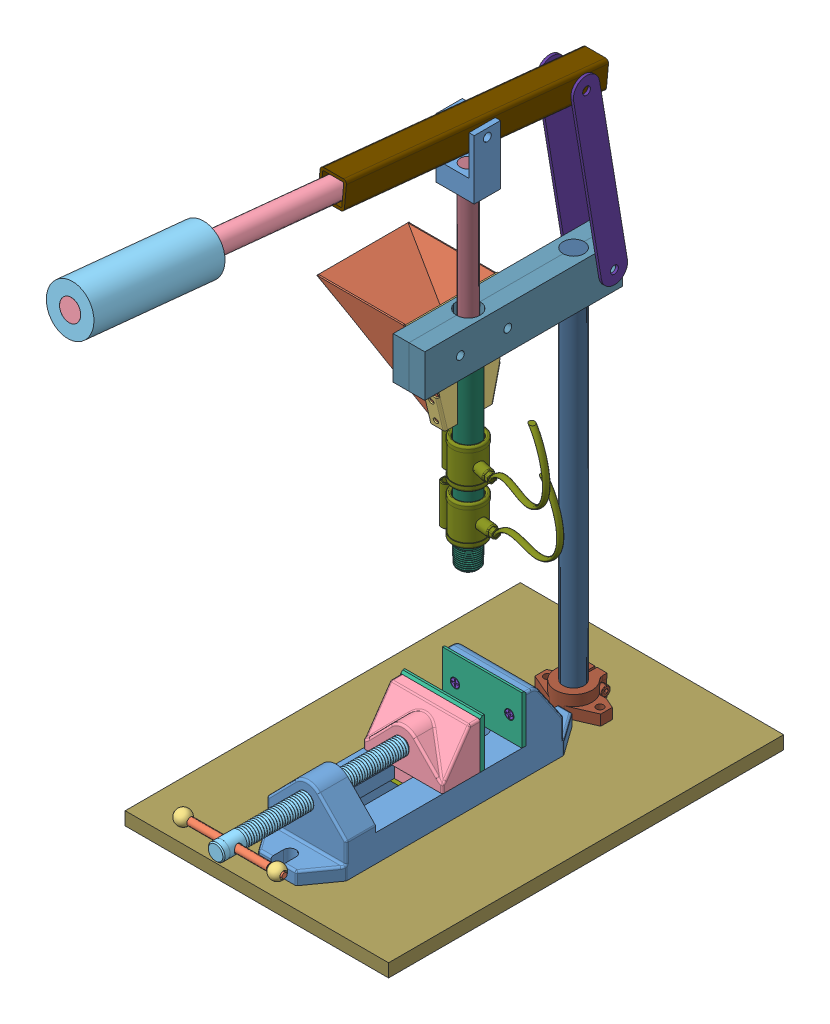
SolidWorks assembly Manual Injection, configuration Varsayılan. Lengths in mm.
Overall size (200 481.82 443.96).
32 component instances, 23 part files, 41 mates.
Components (placement in the parent):
- User Library-Vise-1-1: User Library-Vise-1 [Default] at (-149.6463 -94.0515 315.6053) x (0 0 -1) z (1 0 0) size (256.38 57.15 82.55)
  - User Library-Vise-1_Base-1: User Library-Vise-1_Base [Default] at origin size (209.55 55.56 60.32)
  - User Library-Vise-1_Handle-Rod (6)-1: User Library-Vise-1_Handle-Rod (6) [Default] at (-140.4938 38.1 0) size (5.56 5.56 82.55)
  - User Library-Vise-1_Handle-Ball (7)-1: User Library-Vise-1_Handle-Ball (7) [Default] at (-140.4938 38.1 35.7188) x (1 0 0) z (0 -1 0) size (11.11 10 11.11)
  - User Library-Vise-1_Handle-Ball (7)-2: User Library-Vise-1_Handle-Ball (7) [Default] at (-140.4938 38.1 -35.7188) x (1 0 0) z (0 1 0) size (11.11 10 11.11)
  - User Library-Vise-1_Sliding-Jaw-1: User Library-Vise-1_Sliding-Jaw [Default] at (4.7625 11.0871 0.0381) size (28.57 44.48 60.32)
  - User Library-Vise-1_Screw-1: User Library-Vise-1_Screw [Default] at (-134.1438 38.1 0) size (161.92 12.7 12.7)
  - User Library-Vise-1_Jaw-Plate-1: User Library-Vise-1_Jaw-Plate [Default] at (52.3875 38.8937 0) x (0 0 1) z (-1 0 0) size (60.32 36.51 3.17)
  - User Library-Vise-1_Jaw-Plate-2: User Library-Vise-1_Jaw-Plate [Default] at (20.6375 38.8937 0.0381) x (0 0 -1) z (1 0 0) size (60.32 36.51 3.17)
  - User Library-Vise-1_Retainer-Plate-1: User Library-Vise-1_Retainer-Plate [Default] at (4.7625 9.5504 0.0381) size (25.4 3.17 22.23)
  - flat head screw_ai-5: flat head screw_ai [CR-FHMS 0.138-32x0.375x0.375-N] at (50.7846 38.1 20.6375) size (9.53 6.2 6.2)
  - flat head screw_ai-6: flat head screw_ai [CR-FHMS 0.138-32x0.375x0.375-N] at (50.7846 38.1 -20.6375) size (9.53 6.2 6.2)
  - flat head screw_ai-7: flat head screw_ai [CR-FHMS 0.138-32x0.375x0.375-N] at (22.2404 38.1 20.6756) x (-1 0 0) z (0 1 0) size (9.53 6.2 6.2)
  - flat head screw_ai-8: flat head screw_ai [CR-FHMS 0.138-32x0.375x0.375-N] at (22.2404 38.1 -20.5994) x (-1 0 0) z (0 1 0) size (9.53 6.2 6.2)
  - User Library-Vise-1_Retaining-Screw-2: User Library-Vise-1_Retaining-Screw [HBOLT 0.2500-20x1x1-C] at (4.7625 3.1877 0.0381) x (0 1 0) z (0 0 1) size (30.18 12.85 11.13)
- 5-8inch  rod-2: 5-8inch  rod [Varsayılan] at (-149.6463 -94.0515 195.3553) size (16 300 16)
- support_shf16-1: support_shf16 [Default] at (-149.6463 -94.0515 195.3553) x (1 0 0) z (0 1 0) size (50 31 16)
- base-2: base [Varsayılan] at (-149.6463 -104.0515 285.8553) size (200 10 300)
- 12mm rod-1: 12mm rod [Varsayılan] at (-149.6463 116.8052 275.3553) x (0.940707 0 -0.33922) z (0 1 0) size (12 12 185)
- rod holder-1: rod holder [Varsayılan] at (-161.6463 189.9485 245.3553) x (0 0 -1) z (1 0 0) size (150 32 12)
- 4830K158_STD-WALL TYPE 304-304L SS THRD PIPE NIPPLE-1: 4830K158_STD-WALL TYPE 304-304L SS THRD PIPE NIPPLE [4830K158] at (-149.6463 113.3889 275.3553) x (0 1 0) z (0 0 1) size (152.69 17.99 18.02)
- 75x40 Nozzle Band Heater-1: 75x40 Nozzle Band Heater [Radial] at (-149.6463 55.7599 275.3553) x (-0.103457 0 0.994634) z (-0.994634 0 -0.103457) size (24 75.91 99.43)
- 75x40 Nozzle Band Heater-2: 75x40 Nozzle Band Heater [Radial] at (-149.6463 93.3169 275.3553) x (-0.219712 0 0.975565) z (-0.975565 0 -0.219712) size (24 75.91 99.43)
- rod holder-2: rod holder [Varsayılan] at (-137.6463 189.9485 245.3553) x (0 0 -1) z (-1 0 0) size (150 32 12)
- press handler-1: press handler [Varsayılan] at (-161.6463 254.0801 188.9449) x (0 0.98664 0.162918) z (-1 0 0) size (150 20 2)
- press handler-2: press handler [Varsayılan] at (-135.6463 254.0801 188.9449) x (0 0.98664 0.162918) z (-1 0 0) size (150 20 2)
- 1471T731_SOLID FRAMING-1: 1471T731_SOLID FRAMING [1471T731] at (-149.6463 326.1839 279.1364) x (1 0 0) z (0 0.099653 0.995022) size (20 20 200)
- handler bracket-1: handler bracket [Varsayılan] at (-149.6463 309.3052 265.3553) x (0 -1 0) z (0 0 1) size (45 29 20)
- feeder hole-1: feeder hole [Varsayılan] at (-160.5691 135.7576 275.3553) x (0 0 1) z (-0.707107 -0.707107 0) size (69.96 112.47 47.42)
- feeder hole back-1: feeder hole back [Varsayılan] at (-162.6463 189.9485 275.3553) x (0 0 1) z (-1 0 0) size (70 71.4 14)
- handle pipe-1: handle pipe [Varsayılan] at (-149.6463 331.1665 328.8875) x (-0.854746 -0.516462 0.051724) z (0 0.099653 0.995022) size (16 16 250)
- handle plastics-1: handle plastics [Varsayılan] at (-149.6463 346.1144 478.1408) x (0.970687 0.239151 -0.023951) z (0 0.099653 0.995022) size (36 36 100)
Mates (geometry in assembly coordinates):
- Eş Merkezli3: concentric anti-aligned: cylinder of 5-8inch  rod-2 through (-149.6463 205.9485 195.3553) axis (0 -1 0) radius 8; cylinder of support_shf16-1 through (-149.6463 -95.0515 195.3553) axis (0 1 0) radius 8
- Çakışık10: coincident aligned: plane of 5-8inch  rod-2 through (-149.6463 -94.0515 195.3553) normal (0 -1 0); plane of support_shf16-1 through (-135.6463 -94.0515 181.6381) normal (0 -1 0)
- Eş Merkezli5: concentric anti-aligned: cylinder of User Library-Vise-1-1/User Library-Vise-1_Base-1 through (-149.6463 -84.5265 410.8553) axis (0 -1 0) radius 4.7625; cylinder of base-2 through (-149.6463 -104.0515 410.8553) axis (0 1 0) radius 3
- Eş Merkezli6: concentric anti-aligned: cylinder of User Library-Vise-1-1/User Library-Vise-1_Base-1 through (-149.6463 -84.5265 220.3553) axis (0 -1 0) radius 4.7625; cylinder of base-2 through (-149.6463 -104.0515 220.3553) axis (0 1 0) radius 3
- Çakışık12: coincident anti-aligned: plane of User Library-Vise-1-1/User Library-Vise-1_Base-1 through (-119.4838 -94.0515 398.1553) normal (0 -1 0); plane of base-2 through (-149.6463 -94.0515 285.8553) normal (0 1 0)
- Çakışık13: coincident anti-aligned: plane of support_shf16-1 through (-135.6463 -94.0515 181.6381) normal (0 -1 0); plane of base-2 through (-149.6463 -94.0515 285.8553) normal (0 1 0)
- Eş Merkezli11: concentric anti-aligned: cylinder of 5-8inch  rod-2 through (-149.6463 205.9485 195.3553) axis (0 -1 0) radius 8; cylinder of rod holder-1 through (-149.6463 145.9485 195.3553) axis (0 1 0) radius 8
- Çakışık15: coincident aligned: plane of 5-8inch  rod-2 through (-149.6463 205.9485 195.3553) normal (0 1 0); plane of rod holder-1 through (-149.6463 205.9485 320.3553) normal (0 1 0)
- Eş Merkezli13: concentric anti-aligned: cylinder of 12mm rod-1 through (-149.6463 301.8052 275.3553) axis (0 -1 0) radius 6; cylinder of 4830K158_STD-WALL TYPE 304-304L SS THRD PIPE NIPPLE-1 through (-149.6463 37.0447 275.3553) axis (0 1 0) radius 6.2611
- Çakışık17: coincident aligned: plane of rod holder-1 through (-149.6463 173.9485 320.3553) normal (0 -1 0); circle of 4830K158_STD-WALL TYPE 304-304L SS THRD PIPE NIPPLE-1
- Eş Merkezli14: concentric aligned: cylinder of rod holder-1 through (-149.6463 145.9485 275.3553) axis (0 1 0) radius 9; cylinder of 4830K158_STD-WALL TYPE 304-304L SS THRD PIPE NIPPLE-1 through (-149.6463 113.3889 275.3553) axis (0 1 0) radius 8.5725
- Eş Merkezli15: concentric anti-aligned: cylinder of 4830K158_STD-WALL TYPE 304-304L SS THRD PIPE NIPPLE-1 through (-149.6463 113.3889 275.3553) axis (0 1 0) radius 8.5725; cylinder of 75x40 Nozzle Band Heater-1 through (-149.6463 85.7599 275.3553) axis (0 -1 0) radius 9
- Eş Merkezli16: concentric anti-aligned: cylinder of 4830K158_STD-WALL TYPE 304-304L SS THRD PIPE NIPPLE-1 through (-149.6463 113.3889 275.3553) axis (0 1 0) radius 8.5725; cylinder of 75x40 Nozzle Band Heater-2 through (-149.6463 123.3169 275.3553) axis (0 -1 0) radius 9
- Eş Merkezli17: concentric aligned: cylinder of 5-8inch  rod-2 through (-149.6463 205.9485 195.3553) axis (0 -1 0) radius 8; cylinder of rod holder-2 through (-149.6463 233.9485 195.3553) axis (0 -1 0) radius 8
- Eş Merkezli18: concentric anti-aligned: cylinder of 4830K158_STD-WALL TYPE 304-304L SS THRD PIPE NIPPLE-1 through (-149.6463 113.3889 275.3553) axis (0 1 0) radius 8.5725; cylinder of rod holder-2 through (-149.6463 233.9485 275.3553) axis (0 -1 0) radius 9
- Çakışık19: coincident aligned: plane of rod holder-1 through (-149.6463 205.9485 320.3553) normal (0 1 0); plane of rod holder-2 through (-149.6463 205.9485 320.3553) normal (0 1 0)
- Eş Merkezli19: concentric aligned: cylinder of support_shf16-1 through (-169.6463 -95.0515 195.3553) axis (0 1 0) radius 2.75; cylinder of base-2 through (-169.6463 -104.0515 195.3553) axis (0 1 0) radius 2
- Eş Merkezli20: concentric aligned: cylinder of support_shf16-1 through (-129.6463 -95.0515 195.3553) axis (0 1 0) radius 2.75; cylinder of base-2 through (-129.6463 -104.0515 195.3553) axis (0 1 0) radius 2
- Eş Merkezli21: concentric aligned: cylinder of rod holder-1 through (-179.6463 189.9485 178.3553) axis (1 0 0) radius 3; cylinder of press handler-1 through (-163.6463 189.9485 178.3553) axis (1 0 0) radius 3
- Eş Merkezli22: concentric anti-aligned: cylinder of rod holder-2 through (-119.6463 189.9485 178.3553) axis (-1 0 0) radius 3; cylinder of press handler-2 through (-137.6463 189.9485 178.3553) axis (1 0 0) radius 3
- Çakışık20: coincident anti-aligned: plane of rod holder-1 through (-161.6463 189.9485 245.3553) normal (-1 0 0); plane of press handler-1 through (-161.6463 189.9485 178.3553) normal (1 0 0)
- Çakışık21: coincident anti-aligned: plane of rod holder-2 through (-137.6463 189.9485 245.3553) normal (1 0 0); plane of press handler-2 through (-137.6463 189.9485 178.3553) normal (-1 0 0)
- Eş Merkezli23: concentric aligned: cylinder of press handler-2 through (-137.6463 318.2117 199.5346) axis (1 0 0) radius 3; cylinder of 1471T731_SOLID FRAMING-1 through (-159.9663 318.2117 199.5346) axis (1 0 0) radius 3
- Eş Merkezli24: concentric aligned: cylinder of 12mm rod-1 through (-149.6463 301.8052 275.3553) axis (0 -1 0) radius 6; cylinder of handler bracket-1 through (-149.6463 306.8052 275.3553) axis (0 -1 0) radius 6
- Çakışık22: coincident aligned: plane of 12mm rod-1 through (-149.6463 301.8052 275.3553) normal (0 1 0); plane of handler bracket-1 through (-139.1463 301.8052 285.3553) normal (0 1 0)
- Eş Merkezli25: concentric aligned: cylinder of press handler-1 through (-163.6463 318.2117 199.5346) axis (1 0 0) radius 3; cylinder of 1471T731_SOLID FRAMING-1 through (-159.9663 318.2117 199.5346) axis (1 0 0) radius 3
- Eş Merkezli26: concentric anti-aligned: cylinder of 1471T731_SOLID FRAMING-1 through (-159.9663 325.8052 275.3553) axis (1 0 0) radius 3; cylinder of handler bracket-1 through (-124.1463 325.8052 275.3553) axis (-1 0 0) radius 3
- Uzaklık1: distance = 0.5 mm anti-aligned: plane of 1471T731_SOLID FRAMING-1 through (-139.6463 328.6865 379.386) normal (1 0 0); plane of handler bracket-1 through (-139.1463 331.8052 285.3553) normal (-1 0 0)
- Paralel1: parallel aligned: plane of User Library-Vise-1-1/User Library-Vise-1_Base-1 through (-119.4838 -68.6515 398.1553) normal (1 0 0); plane of rod holder-2 through (-137.6463 189.9485 245.3553) normal (1 0 0)
- Çakışık27: coincident aligned: plane of feeder hole-1 through (-160.3534 136.2489 275.3553) normal (0 1 0); plane of 4830K158_STD-WALL TYPE 304-304L SS THRD PIPE NIPPLE-1 through (-149.6463 136.2489 275.3553) normal (0 1 0)
- Eş Merkezli29: concentric anti-aligned: cylinder of 4830K158_STD-WALL TYPE 304-304L SS THRD PIPE NIPPLE-1 through (-149.6463 113.3889 275.3553) axis (0 1 0) radius 8.5725; cylinder of feeder hole-1 through (-149.6463 145.2489 275.3553) axis (0 -1 0) radius 9
- Paralel4: parallel aligned: plane of rod holder-2 through (-137.6463 189.9485 245.3553) normal (1 0 0); plane of feeder hole-1 through (-149.6463 135.2489 290.3553) normal (1 0 0)
- Eş Merkezli30: concentric anti-aligned: cylinder of rod holder-1 through (-179.6463 189.9485 257.3553) axis (1 0 0) radius 3; cylinder of feeder hole back-1 through (-161.6463 189.9485 257.3553) axis (-1 0 0) radius 2.5
- Eş Merkezli31: concentric anti-aligned: cylinder of rod holder-1 through (-179.6463 189.9485 293.3553) axis (1 0 0) radius 3; cylinder of feeder hole back-1 through (-161.6463 189.9485 293.3553) axis (-1 0 0) radius 2.5
- Çakışık30: coincident anti-aligned: plane of rod holder-1 through (-161.6463 189.9485 245.3553) normal (-1 0 0); plane of feeder hole back-1 through (-161.6463 189.9485 275.3553) normal (1 0 0)
- Teğet3: tangent anti-aligned: plane of 1471T731_SOLID FRAMING-1 through (-157.6463 328.6865 379.386) normal (1 0 0); cylinder of handle pipe-1 through (-149.6463 356.0797 577.643) axis (0 -0.099653 -0.995022) radius 8
- Paralel5: parallel aligned: line of 1471T731_SOLID FRAMING-1 through (-157.6463 328.6865 379.386) axis (0 -0.099653 -0.995022); cylinder of handle pipe-1 through (-149.6463 356.0797 577.643) axis (0 -0.099653 -0.995022) radius 8
- Teğet4: tangent anti-aligned: plane of 1471T731_SOLID FRAMING-1 through (-142.1463 328.189 379.4358) normal (0 0.995022 -0.099653); cylinder of handle pipe-1 through (-149.6463 356.0797 577.643) axis (0 -0.099653 -0.995022) radius 8
- Uzaklık2: distance = 150 mm aligned: plane of handle pipe-1 through (-149.6463 331.1665 328.8875) normal (0 -0.099653 -0.995022); plane of 1471T731_SOLID FRAMING-1 through (-157.1463 323.6813 178.8867) normal (0 -0.099653 -0.995022)
- Eş Merkezli32: concentric aligned: cylinder of handle pipe-1 through (-149.6463 356.0797 577.643) axis (0 -0.099653 -0.995022) radius 8; cylinder of handle plastics-1 through (-149.6463 356.0797 577.643) axis (0 -0.099653 -0.995022) radius 8
- Çakışık33: coincident aligned: circle of handle pipe-1; plane of handle plastics-1 through (-149.6463 356.0797 577.643) normal (0 0.099653 0.995022)
